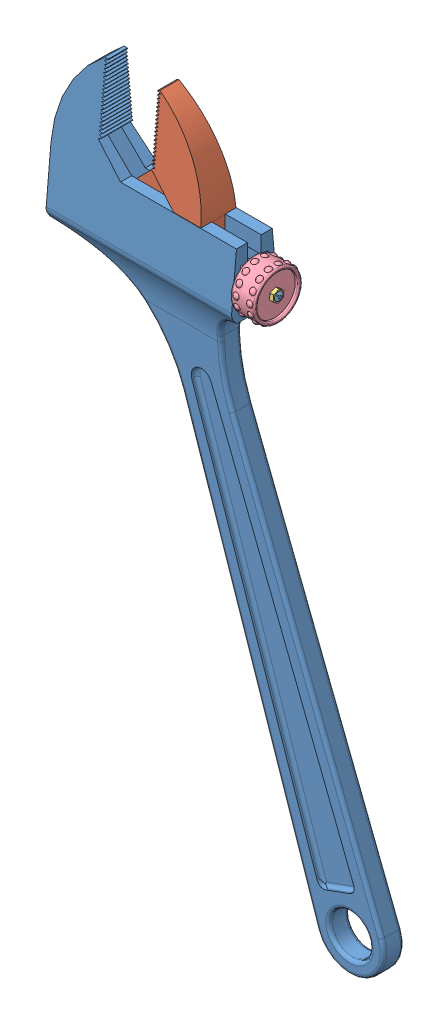
SolidWorks assembly French Key Wrenches, configuration Default. Lengths in mm.
Overall size (97.31 197.07 19.62).
5 component instances, 5 part files, 12 mates.
Components (placement in the parent):
- Part 1-1: Part 1 [Default] at origin size (95.31 197.07 14.83)
- Part 2-1: Part 2 [Default] at (19.0198 -22.4811 0) size (25.07 36.38 10.31)
- Part 3-1: Part 3 [Default] at (-13.336 -38.0758 0.0011) x (0 0.91377 0.406231) z (0 -0.406231 0.91377) size (11.06 63.5 11.06)
- Part 4-1: Part 4 [Default] at (41.07 -38.0758 0.0011) x (1 0 0) z (0 0.91377 0.406231) size (7 14.89 14.82)
- Screw-1: Screw [Default] at (48.164 -38.0758 0.0011) x (0 0.70023 0.713917) z (-1 0 0) size (2.47 2.47 5.52)
Mates (geometry in assembly coordinates):
- Coincident1: coordinate: point of assembly; point of Part 1-1; point of assembly
- Coincident2: coincident: plane of assembly; plane of assembly; plane of Part 1-1 through (-26.9375 0 4) normal (0 0 -1); plane of Part 2-1 through (5.5848 -32.0911 4) normal (0 0 1)
- Coincident5: coincident: plane of assembly; plane of assembly; plane of Part 1-1 through (7.07 -27 7.5) normal (0 1 0); plane of Part 2-1 through (22.5506 -27 7.5) normal (0 -1 0)
- Coincident7: coincident: line of assembly; line of assembly; axis of Part 2-1 through (2.7392 12.2095 -38.0758) axis (0.000001 -1 0); axis of Part 3-1 through (38.664 -38.0758 0.0011) axis (-1 0 0)
- Screw1: screw = 0.5: line of assembly; line of assembly; axis of Part 2-1 through (2.7392 10.2095 -38.0758) axis (0.000001 -1 0); axis of Part 3-1 through (38.664 -38.0758 0.0011) axis (-1 0 0)
- Coincident8: coincident: plane of assembly; plane of assembly; plane of Part 1-1 through (-13.336 -46 7.5) normal (-1 0 0); plane of Part 3-1 through (-13.336 -38.0758 0.0011) normal (1 0 0)
- LimitDistance2: limit distance = 19.0198 mm: plane of assembly; plane of assembly; plane of Part 1-1 through (0 0 0) normal (1 0 0); plane of Part 2-1 through (19.0198 -22.4811 0) normal (1 0 0)
- Coincident12: coincident: plane of assembly; plane of assembly; plane of Part 3-1 through (48.164 -36.8627 -0.8813) normal (0 0.808692 -0.588233); plane of Part 4-1 through (41.07 -36.8627 -0.8813) normal (0 -0.808692 0.588233)
- Coincident13: coincident: plane of assembly; plane of assembly; plane of Part 3-1 through (48.164 -37.9181 1.4928) normal (0 0.105079 0.994464); plane of Part 4-1 through (41.07 -37.9181 1.4928) normal (0 -0.105079 -0.994464)
- Coincident15: coincident: plane of assembly; plane of assembly; plane of Part 1-1 through (41.07 -27 7.5) normal (1 0 0); plane of Part 4-1 through (41.07 -38.0758 0.0011) normal (-1 0 0)
- Concentric2: concentric: cylinder of assembly; cylinder of assembly; cylinder of Part 3-1 through (43.664 -38.0758 0.0011) axis (1 0 0) radius 0.5; cylinder of Screw-1 through (43.164 -38.0758 0.0011) axis (1 0 0) radius 0.5
- Coincident16: coincident: plane of assembly; plane of assembly; plane of Part 3-1 through (48.164 -38.0758 0.0011) normal (1 0 0); plane of Screw-1 through (48.164 -38.0758 0.0011) normal (-1 0 0)
